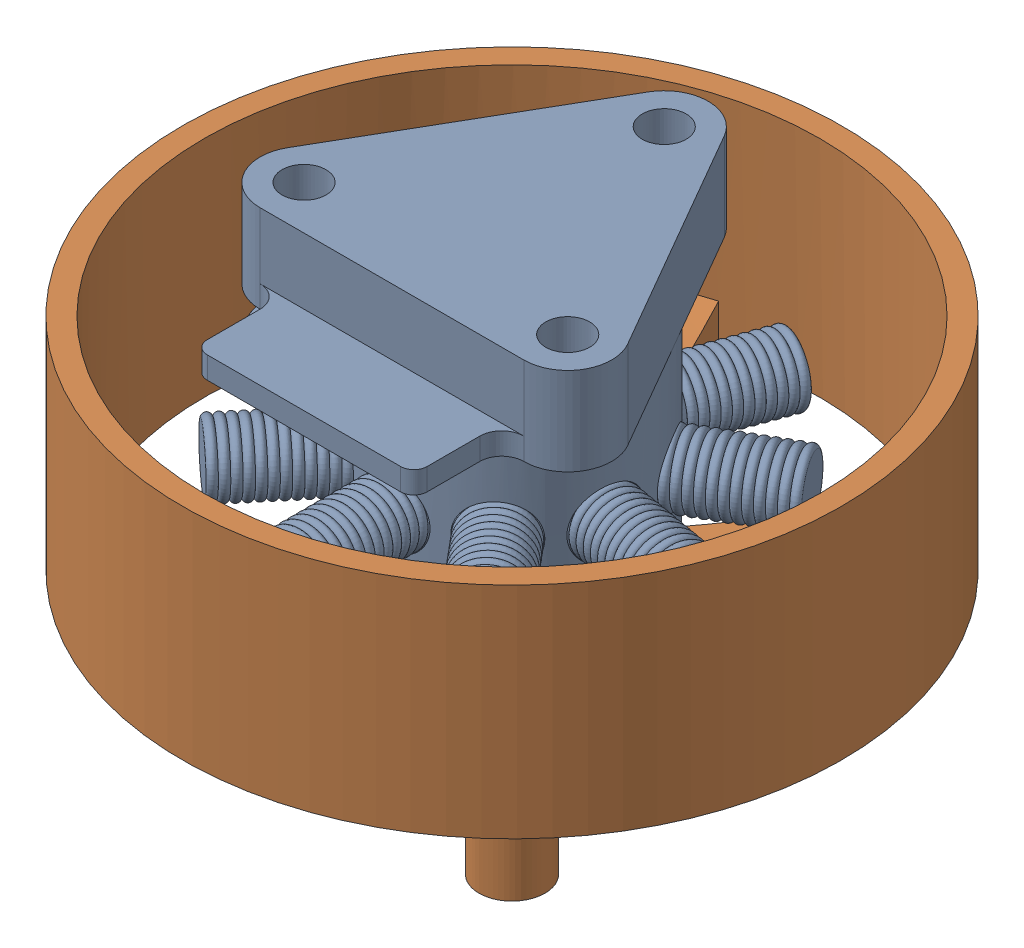
SolidWorks assembly Motor, configuration Valor predeterminado. Lengths in mm.
Overall size (17.22 13 17.22).
2 component instances, 2 part files, 2 mates.
Components (placement in the parent):
- Bobina motor-1: Bobina motor [Valor predeterminado] at (-0.2271 1.9668 10.0433) size (10.08 6 9.93)
- Carcaça motor-1: Carcaça motor [Valor predeterminado] at (-0.2271 1.9668 10.0433) x (0.160836 0 -0.986981) z (-0.986981 0 -0.160836) size (15 11 15)
Mates (geometry in assembly coordinates):
- Coincidente1: coincident anti-aligned: plane of Bobina motor-1 through (2.7729 1.9668 11.7754) normal (0 -1 0); plane of Carcaça motor-1 through (-0.2271 1.9668 10.0433) normal (0 1 0)
- Concêntrico1: concentric aligned: cylinder of Bobina motor-1 through (-0.2271 -2.0332 10.0433) axis (0 1 0) radius 2.7321; cylinder of Carcaça motor-1 through (-0.2271 -4.0332 10.0433) axis (0 1 0) radius 7
